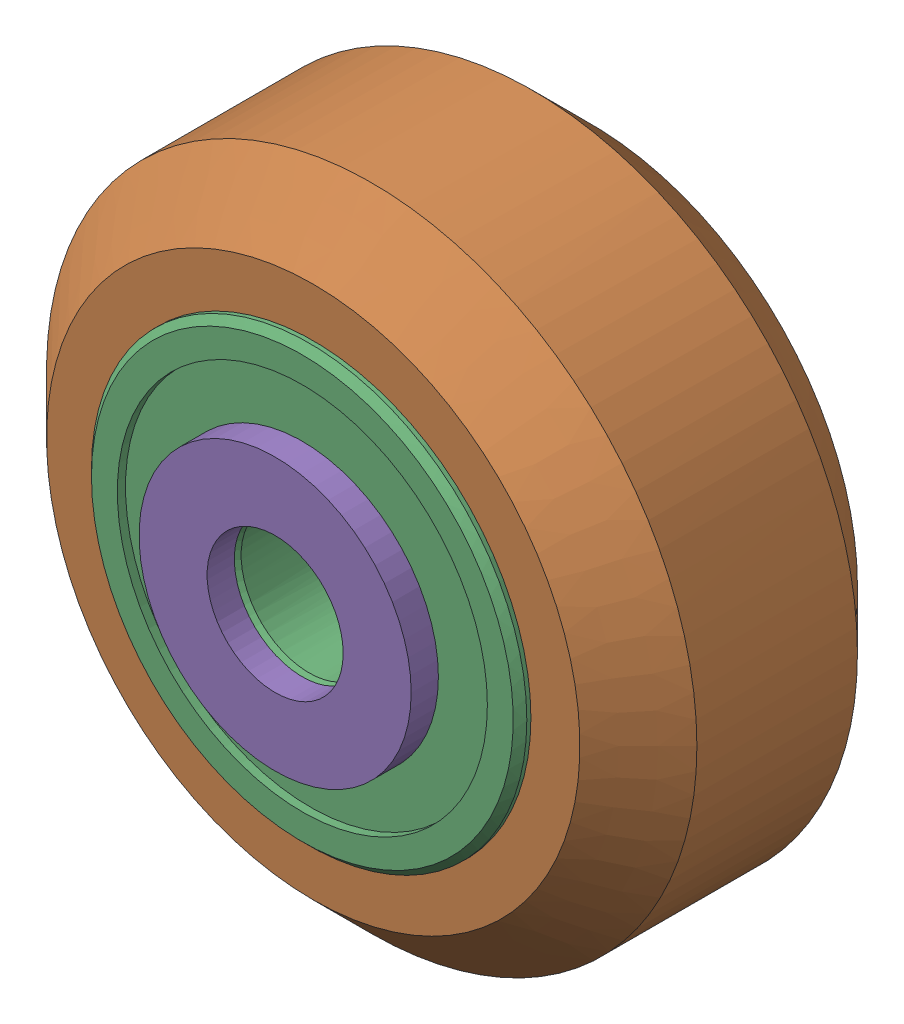
SolidWorks assembly Xtreme Solid V Wheel Kit Assembly_7, configuration Default. Lengths in mm.
Overall size (23.9 23.9 13).
6 component instances, 3 part files, 0 mates.
Components (placement in the parent):
- Precision Shim - 10x5x1mm-1: Precision Shim - 10x5x1mm [Default] at origin size (10 10 1)
- Xtreme Solid V Wheel Assembly_7-1: Xtreme Solid V Wheel Assembly_7 [Default] at (115.15 25.79 -23.5) size (23.9 23.9 11)
  - Xtreme Solid V Wheel-1: Xtreme Solid V Wheel [Default] at (-115.15 -25.79 30) x (0 0 1) z (-1 0 0) size (10.2 23.9 23.9)
  - Wheel+Kit+-+5x16x5mm+Sealed+Radial+Ball+Bearing.step.f3d-1: Wheel+Kit+-+5x16x5mm+Sealed+Radial+Ball+Bearing.step.f3d [Default] at (-115.15 -25.79 30) x (0 1 0) z (-1 0 0) size (16 5 16)
  - Wheel+Kit+-+5x16x5mm+Sealed+Radial+Ball+Bearing.step.f3d-2: Wheel+Kit+-+5x16x5mm+Sealed+Radial+Ball+Bearing.step.f3d [Default] at (-115.15 -25.79 30) x (0 1 0) z (1 0 0) size (16 5 16)
- Precision Shim - 10x5x1mm-2: Precision Shim - 10x5x1mm [Default] at (0 0 12) size (10 10 1)
